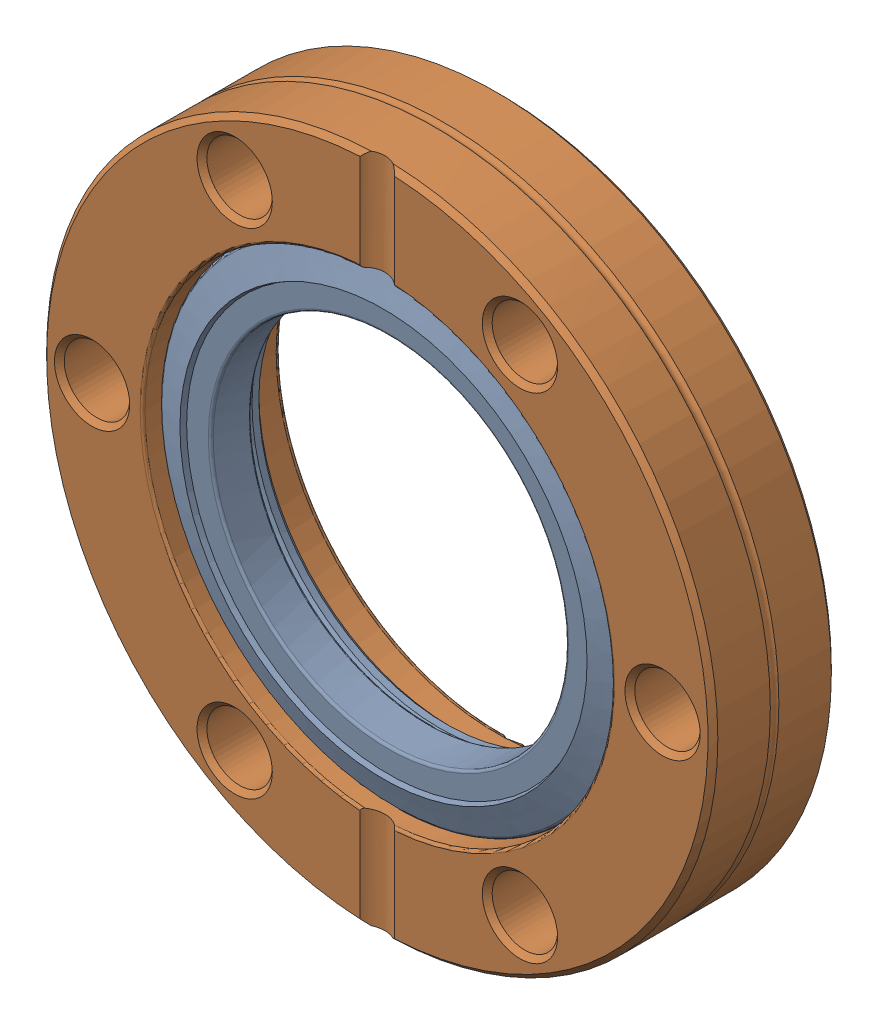
SolidWorks assembly A0000603, configuration Default. Lengths in mm.
Overall size (69.09 69.09 12.74).
2 component instances, 2 part files, 0 mates.
Components (placement in the parent):
- Er Source P2-1-2_P0000489-1: Er Source P2-1-2_P0000489 [Default] at (0 0 8.5725) size (48.21 48.21 6.99)
- Er Source P2-1-1_P0000436-1: Er Source P2-1-1_P0000436 [Default] at (0 0 6.35) x (-1 0 0) z (0 0 -1) size (69.09 69.09 12.74)
